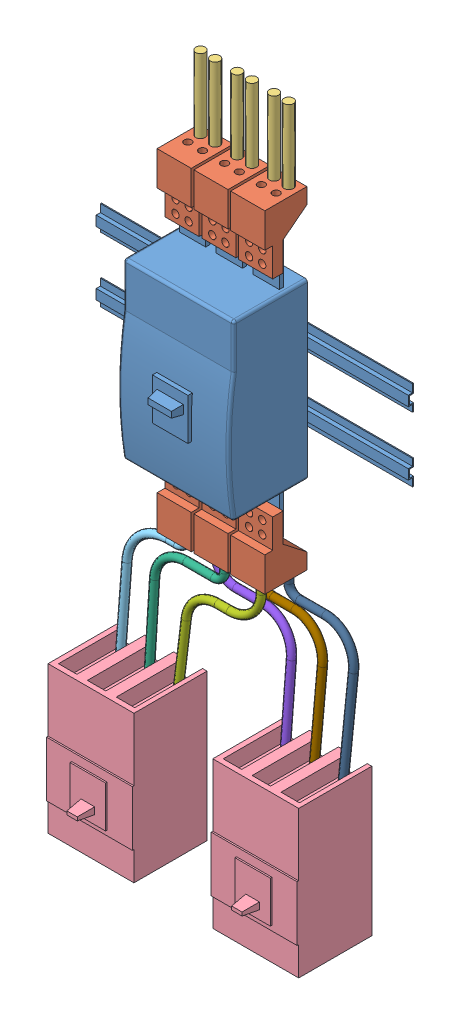
SolidWorks assembly Ensamble tablero de ditribución 2, configuration Predeterminado. Lengths in mm.
Overall size (594 1300.5 196).
23 component instances, 12 part files, 62 mates.
Components (placement in the parent):
- INTERRUPTOR DE 1000 AMP-1: INTERRUPTOR DE 1000 AMP [Predeterminado] at (-1201.779 1141.3984 2879.7748) size (594 494 186)
- zapata interup 1000 amp-1: zapata interup 1000 amp [Predeterminado] at (-1271.779 1397.3984 2878.2748) size (65 120 80)
- zapata interup 1000 amp-2: zapata interup 1000 amp [Predeterminado] at (-1201.779 1397.3984 2878.2748) size (65 120 80)
- zapata interup 1000 amp-3: zapata interup 1000 amp [Predeterminado] at (-1131.779 1397.3984 2878.2748) size (65 120 80)
- zapata interup 1000 amp-7: zapata interup 1000 amp [Predeterminado] at (-1271.779 885.3984 2878.2748) x (-1 0 0) z (0 0 1) size (65 120 80)
- zapata interup 1000 amp-8: zapata interup 1000 amp [Predeterminado] at (-1201.779 885.3984 2878.2748) x (-1 0 0) z (0 0 1) size (65 120 80)
- zapata interup 1000 amp-9: zapata interup 1000 amp [Predeterminado] at (-1131.779 885.3984 2878.2748) x (-1 0 0) z (0 0 1) size (65 120 80)
- TABLERO DE D. 15-5-19-1: TABLERO DE D. 15-5-19 [Predeterminado] at (-1201.779 603.8984 2035.8616) size (920 2005 1035) (hidden)
- CABLE INTERRUP 1000-1: CABLE INTERRUP 1000 [Predeterminado] at (-1285.779 1597.3984 2894.2748) x (0.998379 0 0.056922) z (0 -1 0) size (18 18 140)
- CABLE INTERRUP 1000-2: CABLE INTERRUP 1000 [Predeterminado] at (-1257.779 1597.3984 2894.2748) x (0.733767 0 0.679401) z (0 -1 0) size (18 18 140)
- CABLE INTERRUP 1000-3: CABLE INTERRUP 1000 [Predeterminado] at (-1215.779 1597.3984 2894.2748) x (1 0 0) z (0 -1 0) size (18 18 140)
- CABLE INTERRUP 1000-4: CABLE INTERRUP 1000 [Predeterminado] at (-1187.779 1597.3984 2894.2748) x (1 0 0) z (0 -1 0) size (18 18 140)
- CABLE INTERRUP 1000-5: CABLE INTERRUP 1000 [Predeterminado] at (-1145.779 1597.3984 2894.2748) x (0.945572 0 0.325412) z (0 -1 0) size (18 18 140)
- CABLE INTERRUP 1000-6: CABLE INTERRUP 1000 [Predeterminado] at (-1117.779 1597.3984 2894.2748) x (1 0 0) z (0 -1 0) size (18 18 140)
- INTERRUPTOR DE BAJA-1: INTERRUPTOR DE BAJA [Predeterminado] at (-1276.779 436.6484 2960.2748) x (0 0 1) z (-1 0 0) size (175 279.5 163.5)
- INTERRUPTOR DE BAJA-3: INTERRUPTOR DE BAJA [Predeterminado] at (-963.279 436.6484 2960.2748) x (0 0 1) z (-1 0 0) size (175 279.5 163.5)
- Pieza1^Ensamble tablero de ditribución 2-1: Pieza1^Ensamble tablero de ditribución 2 [Predeterminado] at (-1271.779 825.3984 2878.2748) x (-1 0 0) z (0 -1 0) size (140.98 15.38 279.5) (virtual)
- Pieza2^Ensamble tablero de ditribución 2-1: Pieza2^Ensamble tablero de ditribución 2 [Predeterminado] at (-1201.779 825.3984 2878.2748) x (-1 0 0) z (0 -1 0) size (155.99 15.38 279.4) (virtual)
- Pieza3^Ensamble tablero de ditribución 2-1: Pieza3^Ensamble tablero de ditribución 2 [Predeterminado] at (-1131.779 825.3984 2878.2748) x (-1 0 0) z (0 -1 0) size (170.95 15.38 279.81) (virtual)
- Pieza4^Ensamble tablero de ditribución 2-1: Pieza4^Ensamble tablero de ditribución 2 [Predeterminado] at (-1271.779 825.3984 2878.2748) x (-1 0 0) z (0 -1 0) size (172.49 39.32 279.93) (virtual)
- Pieza5^Ensamble tablero de ditribución 2-2: Pieza5^Ensamble tablero de ditribución 2 [Predeterminado] at (-1201.779 825.3984 2878.2748) x (-1 0 0) z (0 -1 0) size (157.5 39.33 279.81) (virtual)
- Pieza6^Ensamble tablero de ditribución 2-1: Pieza6^Ensamble tablero de ditribución 2 [Predeterminado] at origin (virtual)
- Pieza7^Ensamble tablero de ditribución 2-1: Pieza7^Ensamble tablero de ditribución 2 [Predeterminado] at (-1131.779 825.3984 2878.2748) x (-1 0 0) z (0 -1 0) size (143.62 39.34 279.74) (virtual)
Mates (geometry in assembly coordinates):
- Coincidente4: coincident anti-aligned: plane of INTERRUPTOR DE 1000 AMP-1 through (-1014.3897 1388.3984 2923.2748) normal (0 0 1); plane of zapata interup 1000 amp-1 through (-1319.279 1337.3984 2923.2748) normal (0 0 -1)
- Concéntrica1: concentric aligned: cylinder of INTERRUPTOR DE 1000 AMP-1 through (-1284.279 1352.3984 2895.4758) axis (0 0 1) radius 7; cylinder of zapata interup 1000 amp-1 through (-1284.279 1352.3984 2903.4758) axis (0 0 1) radius 7
- Coincidente5: coincident anti-aligned: plane of INTERRUPTOR DE 1000 AMP-1 through (-1014.3897 1388.3984 2923.2748) normal (0 0 1); plane of zapata interup 1000 amp-2 through (-1249.279 1337.3984 2923.2748) normal (0 0 -1)
- Concéntrica2: concentric aligned: cylinder of INTERRUPTOR DE 1000 AMP-1 through (-1189.279 1352.3984 2895.4758) axis (0 0 1) radius 7; cylinder of zapata interup 1000 amp-2 through (-1189.279 1352.3984 2903.4758) axis (0 0 1) radius 7
- Coincidente6: coincident anti-aligned: plane of INTERRUPTOR DE 1000 AMP-1 through (-1014.3897 1388.3984 2923.2748) normal (0 0 1); plane of zapata interup 1000 amp-3 through (-1179.279 1337.3984 2923.2748) normal (0 0 -1)
- Concéntrica4: concentric aligned: cylinder of INTERRUPTOR DE 1000 AMP-1 through (-1144.279 1352.3984 2895.4758) axis (0 0 1) radius 7; cylinder of zapata interup 1000 amp-3 through (-1144.279 1352.3984 2903.4758) axis (0 0 1) radius 7
- Coincidente8: coincident anti-aligned: plane of INTERRUPTOR DE 1000 AMP-1 through (-1014.3897 894.3984 2923.2748) normal (0 0 1); plane of zapata interup 1000 amp-9 through (-1084.279 945.3984 2923.2748) normal (0 0 -1)
- Ancho3: width aligned: plane of zapata interup 1000 amp-9 through (-1099.279 945.3984 2958.2748) normal (1 0 0); plane of zapata interup 1000 amp-9 through (-1164.279 945.3984 2958.2748) normal (-1 0 0); plane of INTERRUPTOR DE 1000 AMP-1 through (-1106.779 976.3984 2830.871) normal (1 0 0); plane of INTERRUPTOR DE 1000 AMP-1 through (-1156.779 976.3984 2830.871) normal (-1 0 0)
- Concéntrica5: concentric aligned: cylinder of INTERRUPTOR DE 1000 AMP-1 through (-1119.279 906.3984 2894.6673) axis (0 0 1) radius 7; cylinder of zapata interup 1000 amp-9 through (-1119.279 906.3984 2903.4758) axis (0 0 1) radius 7
- Coincidente10: coincident anti-aligned: plane of INTERRUPTOR DE 1000 AMP-1 through (-1014.3897 894.3984 2923.2748) normal (0 0 1); plane of zapata interup 1000 amp-8 through (-1154.279 945.3984 2923.2748) normal (0 0 -1)
- Ancho4: width aligned: plane of zapata interup 1000 amp-8 through (-1169.279 945.3984 2958.2748) normal (1 0 0); plane of zapata interup 1000 amp-8 through (-1234.279 945.3984 2958.2748) normal (-1 0 0); plane of INTERRUPTOR DE 1000 AMP-1 through (-1176.779 976.3984 2830.871) normal (1 0 0); plane of INTERRUPTOR DE 1000 AMP-1 through (-1226.779 976.3984 2830.871) normal (-1 0 0)
- Coincidente11: coincident anti-aligned: plane of INTERRUPTOR DE 1000 AMP-1 through (-1014.3897 894.3984 2923.2748) normal (0 0 1); plane of zapata interup 1000 amp-7 through (-1224.279 945.3984 2923.2748) normal (0 0 -1)
- Ancho5: width aligned: plane of zapata interup 1000 amp-7 through (-1304.279 945.3984 2958.2748) normal (-1 0 0); plane of zapata interup 1000 amp-7 through (-1239.279 945.3984 2958.2748) normal (1 0 0); plane of INTERRUPTOR DE 1000 AMP-1 through (-1296.779 976.3984 2830.871) normal (-1 0 0); plane of INTERRUPTOR DE 1000 AMP-1 through (-1246.779 976.3984 2830.871) normal (1 0 0)
- Concéntrica6: concentric aligned: cylinder of INTERRUPTOR DE 1000 AMP-1 through (-1214.279 906.3984 2894.6673) axis (0 0 1) radius 7; cylinder of zapata interup 1000 amp-8 through (-1214.279 906.3984 2903.4758) axis (0 0 1) radius 7
- Concéntrica7: concentric aligned: cylinder of INTERRUPTOR DE 1000 AMP-1 through (-1259.279 906.3984 2894.6673) axis (0 0 1) radius 7; cylinder of zapata interup 1000 amp-7 through (-1259.279 906.3984 2903.4758) axis (0 0 1) radius 7
- Coincidente37: coincident aligned: plane of INTERRUPTOR DE 1000 AMP-1 through (-1201.779 1141.3984 3055.7748) normal (0 0 1); plane of TABLERO DE D. 15-5-19-1 through (-1601.779 1679.1188 3055.7748) normal (0 0 1)
- Ancho13: width aligned: plane of TABLERO DE D. 15-5-19-1 through (-1661.779 -398.6016 3070.8616) normal (-1 0 0); plane of TABLERO DE D. 15-5-19-1 through (-741.779 -398.6016 3070.8616) normal (1 0 0); plane of INTERRUPTOR DE 1000 AMP-1 through (-1306.779 976.3984 3029.7748) normal (-1 0 0); plane of INTERRUPTOR DE 1000 AMP-1 through (-1096.779 976.3984 3029.7748) normal (1 0 0)
- Distancia4: distance = 300 mm aligned: plane of TABLERO DE D. 15-5-19-1 through (-1661.779 1606.3984 3070.8616) normal (0 1 0); plane of INTERRUPTOR DE 1000 AMP-1 through (-1306.779 1306.3984 3029.7748) normal (0 1 0)
- Concéntrica8: concentric aligned: cylinder of zapata interup 1000 amp-1 through (-1285.779 1447.3984 2894.2748) axis (0 1 0) radius 7; cylinder of CABLE INTERRUP 1000-1 through (-1285.779 1457.3984 2894.2748) axis (0 1 0) radius 9
- Paralelo1: parallel aligned: plane of INTERRUPTOR DE 1000 AMP-1 through (-1296.779 1388.3984 2830.871) normal (-1 0 0); plane of zapata interup 1000 amp-1 through (-1304.279 1337.3984 2958.2748) normal (-1 0 0)
- Coincidente65: coincident anti-aligned: plane of zapata interup 1000 amp-1 through (-1304.279 1457.3984 2958.2748) normal (0 1 0); plane of CABLE INTERRUP 1000-1 through (-1285.779 1457.3984 2894.2748) normal (0 -1 0)
- Concéntrica9: concentric aligned: cylinder of zapata interup 1000 amp-1 through (-1257.779 1447.3984 2894.2748) axis (0 1 0) radius 7; cylinder of CABLE INTERRUP 1000-2 through (-1257.779 1457.3984 2894.2748) axis (0 1 0) radius 9
- Coincidente66: coincident anti-aligned: plane of zapata interup 1000 amp-1 through (-1304.279 1457.3984 2958.2748) normal (0 1 0); plane of CABLE INTERRUP 1000-2 through (-1257.779 1457.3984 2894.2748) normal (0 -1 0)
- Concéntrica10: concentric aligned: cylinder of zapata interup 1000 amp-2 through (-1215.779 1447.3984 2894.2748) axis (0 1 0) radius 7; cylinder of CABLE INTERRUP 1000-3 through (-1215.779 1457.3984 2894.2748) axis (0 1 0) radius 9
- Coincidente67: coincident anti-aligned: plane of zapata interup 1000 amp-2 through (-1234.279 1457.3984 2958.2748) normal (0 1 0); plane of CABLE INTERRUP 1000-3 through (-1215.779 1457.3984 2894.2748) normal (0 -1 0)
- Concéntrica11: concentric aligned: cylinder of zapata interup 1000 amp-2 through (-1187.779 1447.3984 2894.2748) axis (0 1 0) radius 7; cylinder of CABLE INTERRUP 1000-4 through (-1187.779 1457.3984 2894.2748) axis (0 1 0) radius 9
- Coincidente68: coincident anti-aligned: plane of zapata interup 1000 amp-2 through (-1234.279 1457.3984 2958.2748) normal (0 1 0); plane of CABLE INTERRUP 1000-4 through (-1187.779 1457.3984 2894.2748) normal (0 -1 0)
- Concéntrica12: concentric aligned: cylinder of zapata interup 1000 amp-3 through (-1145.779 1447.3984 2894.2748) axis (0 1 0) radius 7; cylinder of CABLE INTERRUP 1000-5 through (-1145.779 1457.3984 2894.2748) axis (0 1 0) radius 9
- Paralelo2: parallel aligned: plane of INTERRUPTOR DE 1000 AMP-1 through (-1106.779 1306.3984 2830.871) normal (1 0 0); plane of zapata interup 1000 amp-3 through (-1099.279 1337.3984 2958.2748) normal (1 0 0)
- Coincidente69: coincident anti-aligned: plane of zapata interup 1000 amp-3 through (-1164.279 1457.3984 2958.2748) normal (0 1 0); plane of CABLE INTERRUP 1000-5 through (-1145.779 1457.3984 2894.2748) normal (0 -1 0)
- Concéntrica13: concentric aligned: cylinder of zapata interup 1000 amp-3 through (-1117.779 1447.3984 2894.2748) axis (0 1 0) radius 7; cylinder of CABLE INTERRUP 1000-6 through (-1117.779 1457.3984 2894.2748) axis (0 1 0) radius 9
- Coincidente70: coincident anti-aligned: plane of zapata interup 1000 amp-3 through (-1164.279 1457.3984 2958.2748) normal (0 1 0); plane of CABLE INTERRUP 1000-6 through (-1117.779 1457.3984 2894.2748) normal (0 -1 0)
- Coincidente71: coincident aligned: plane of INTERRUPTOR DE 1000 AMP-1 through (-1201.779 1141.3984 3035.7748) normal (0 0 1); plane of INTERRUPTOR DE BAJA-1 through (-1276.779 436.6484 3035.7748) normal (0 0 1)
- Distancia5: distance = 400 mm anti-aligned: plane of INTERRUPTOR DE 1000 AMP-1 through (-1306.779 976.3984 3029.7748) normal (0 -1 0); plane of INTERRUPTOR DE BAJA-1 through (-1440.279 576.3984 2890.7748) normal (0 1 0)
- Distancia6: distance = 400 mm anti-aligned: plane of INTERRUPTOR DE 1000 AMP-1 through (-1306.779 976.3984 3029.7748) normal (0 -1 0); plane of INTERRUPTOR DE BAJA-3 through (-1126.779 576.3984 2890.7748) normal (0 1 0)
- Coincidente75: coincident aligned: plane of INTERRUPTOR DE BAJA-1 through (-1276.779 436.6484 3035.7748) normal (0 0 1); plane of INTERRUPTOR DE BAJA-3 through (-963.279 436.6484 3035.7748) normal (0 0 1)
- Distancia7: distance = 150 mm anti-aligned: plane of INTERRUPTOR DE BAJA-1 through (-1276.779 436.6484 2960.2748) normal (1 0 0); plane of INTERRUPTOR DE BAJA-3 through (-1126.779 436.6484 2960.2748) normal (-1 0 0)
- Ancho14: width anti-aligned: plane of TABLERO DE D. 15-5-19-1 through (-1531.279 1728.1511 2962.8616) normal (1 0 0); plane of TABLERO DE D. 15-5-19-1 through (-872.279 1728.1511 2962.8616) normal (-1 0 0); plane of INTERRUPTOR DE BAJA-1 through (-1440.279 436.6484 2960.2748) normal (-1 0 0); plane of INTERRUPTOR DE BAJA-3 through (-963.279 436.6484 2960.2748) normal (1 0 0)
- EnPosición1: in place: plane of zapata interup 1000 amp-7 through (-1239.279 825.3984 2958.2748) normal (0 -1 0); plane of ? through (0 825.3984 0) normal (0 -1 0); moOrthogonalPlaneRef_w of zapata interup 1000 amp-7 through (-1239.279 825.3984 2958.2748) normal (0 -1 0); unknown of ?; plane of zapata interup 1000 amp-7 through (-1239.279 825.3984 2958.2748) normal (0 -1 0); line of ? through (-55 0 825.3984) axis (0 -1 0); plane of zapata interup 1000 amp-7 through (-1239.279 825.3984 2958.2748) normal (0 -1 0); unknown of ?
- Coincidente96: coincident aligned: plane of zapata interup 1000 amp-7; plane of Pieza1^Ensamble tablero de ditribución 2-1
- Coincidente97: coincident aligned: moOrthogonalPlaneRef_w of zapata interup 1000 amp-7 through (-1271.779 825.3984 2878.2748) normal (0 0 -1); plane of Pieza1^Ensamble tablero de ditribución 2-1
- Coincidente98: coincident anti-aligned: moOrthogonalPlaneRef_w of zapata interup 1000 amp-7 through (-1271.779 825.3984 2878.2748) normal (1 0 0); plane of Pieza1^Ensamble tablero de ditribución 2-1
- EnPosición2: in place: plane of zapata interup 1000 amp-8 through (-1169.279 825.3984 2958.2748) normal (0 -1 0); plane of ? through (0 825.3984 0) normal (0 -1 0); plane of zapata interup 1000 amp-8 through (-1169.279 825.3984 2958.2748) normal (0 -1 0); unknown of ?; plane of zapata interup 1000 amp-8 through (-1169.279 825.3984 2958.2748) normal (0 -1 0); line of ? through (-55 0 825.3984) axis (0 -1 0); plane of zapata interup 1000 amp-8 through (-1169.279 825.3984 2958.2748) normal (0 -1 0); unknown of ?
- Coincidente99: coincident aligned: plane of zapata interup 1000 amp-8; plane of Pieza2^Ensamble tablero de ditribución 2-1
- Coincidente100: coincident aligned: moOrthogonalPlaneRef_w of zapata interup 1000 amp-8 through (-1201.779 825.3984 2878.2748) normal (0 0 -1); plane of Pieza2^Ensamble tablero de ditribución 2-1
- Coincidente101: coincident anti-aligned: moOrthogonalPlaneRef_w of zapata interup 1000 amp-8 through (-1201.779 825.3984 2878.2748) normal (1 0 0); plane of Pieza2^Ensamble tablero de ditribución 2-1
- EnPosición3: in place: plane of zapata interup 1000 amp-9 through (-1099.279 825.3984 2958.2748) normal (0 -1 0); plane of ? through (0 825.3984 0) normal (0 -1 0); plane of zapata interup 1000 amp-9 through (-1099.279 825.3984 2958.2748) normal (0 -1 0); unknown of ?; plane of zapata interup 1000 amp-9 through (-1099.279 825.3984 2958.2748) normal (0 -1 0); line of ? through (-55 0 825.3984) axis (0 -1 0); plane of zapata interup 1000 amp-9 through (-1099.279 825.3984 2958.2748) normal (0 -1 0); unknown of ?
- Coincidente102: coincident aligned: plane of zapata interup 1000 amp-9; plane of Pieza3^Ensamble tablero de ditribución 2-1
- Coincidente103: coincident aligned: moOrthogonalPlaneRef_w of zapata interup 1000 amp-9 through (-1131.779 825.3984 2878.2748) normal (0 0 -1); plane of Pieza3^Ensamble tablero de ditribución 2-1
- Coincidente104: coincident anti-aligned: moOrthogonalPlaneRef_w of zapata interup 1000 amp-9 through (-1131.779 825.3984 2878.2748) normal (1 0 0); plane of Pieza3^Ensamble tablero de ditribución 2-1
- EnPosición4: in place: plane of zapata interup 1000 amp-7 through (-1239.279 825.3984 2958.2748) normal (0 -1 0); plane of ? through (0 825.3984 0) normal (0 -1 0); plane of zapata interup 1000 amp-7 through (-1239.279 825.3984 2958.2748) normal (0 -1 0); unknown of ?; plane of zapata interup 1000 amp-7 through (-1239.279 825.3984 2958.2748) normal (0 -1 0); line of ? through (-55 0 825.3984) axis (0 -1 0); plane of zapata interup 1000 amp-7 through (-1239.279 825.3984 2958.2748) normal (0 -1 0); unknown of ?
- Coincidente105: coincident aligned: plane of zapata interup 1000 amp-7; plane of Pieza4^Ensamble tablero de ditribución 2-1
- Coincidente106: coincident aligned: moOrthogonalPlaneRef_w of zapata interup 1000 amp-7 through (-1271.779 825.3984 2878.2748) normal (0 0 -1); plane of Pieza4^Ensamble tablero de ditribución 2-1
- Coincidente107: coincident anti-aligned: moOrthogonalPlaneRef_w of zapata interup 1000 amp-7 through (-1271.779 825.3984 2878.2748) normal (1 0 0); plane of Pieza4^Ensamble tablero de ditribución 2-1
- EnPosición5: in place: plane of zapata interup 1000 amp-8 through (-1169.279 825.3984 2958.2748) normal (0 -1 0); plane of ? through (0 825.3984 0) normal (0 -1 0); plane of zapata interup 1000 amp-8 through (-1169.279 825.3984 2958.2748) normal (0 -1 0); unknown of ?; plane of zapata interup 1000 amp-8 through (-1169.279 825.3984 2958.2748) normal (0 -1 0); line of ? through (-55 0 825.3984) axis (0 -1 0); plane of zapata interup 1000 amp-8 through (-1169.279 825.3984 2958.2748) normal (0 -1 0); unknown of ?
- Coincidente108: coincident aligned: plane of zapata interup 1000 amp-8; plane of Pieza5^Ensamble tablero de ditribución 2-2
- Coincidente109: coincident aligned: moOrthogonalPlaneRef_w of zapata interup 1000 amp-8 through (-1201.779 825.3984 2878.2748) normal (0 0 -1); plane of Pieza5^Ensamble tablero de ditribución 2-2
- Coincidente110: coincident anti-aligned: moOrthogonalPlaneRef_w of zapata interup 1000 amp-8 through (-1201.779 825.3984 2878.2748) normal (1 0 0); plane of Pieza5^Ensamble tablero de ditribución 2-2
- EnPosición6: in place: plane of zapata interup 1000 amp-9 through (-1099.279 825.3984 2958.2748) normal (0 -1 0); plane of ? through (0 825.3984 0) normal (0 -1 0); plane of zapata interup 1000 amp-9 through (-1099.279 825.3984 2958.2748) normal (0 -1 0); unknown of ?; plane of zapata interup 1000 amp-9 through (-1099.279 825.3984 2958.2748) normal (0 -1 0); line of ? through (-55 0 825.3984) axis (0 -1 0); plane of zapata interup 1000 amp-9 through (-1099.279 825.3984 2958.2748) normal (0 -1 0); unknown of ?
- Coincidente111: coincident aligned: plane of zapata interup 1000 amp-9; plane of Pieza7^Ensamble tablero de ditribución 2-1
- Coincidente112: coincident aligned: moOrthogonalPlaneRef_w of zapata interup 1000 amp-9 through (-1131.779 825.3984 2878.2748) normal (0 0 -1); plane of Pieza7^Ensamble tablero de ditribución 2-1
- Coincidente113: coincident anti-aligned: moOrthogonalPlaneRef_w of zapata interup 1000 amp-9 through (-1131.779 825.3984 2878.2748) normal (1 0 0); plane of Pieza7^Ensamble tablero de ditribución 2-1
